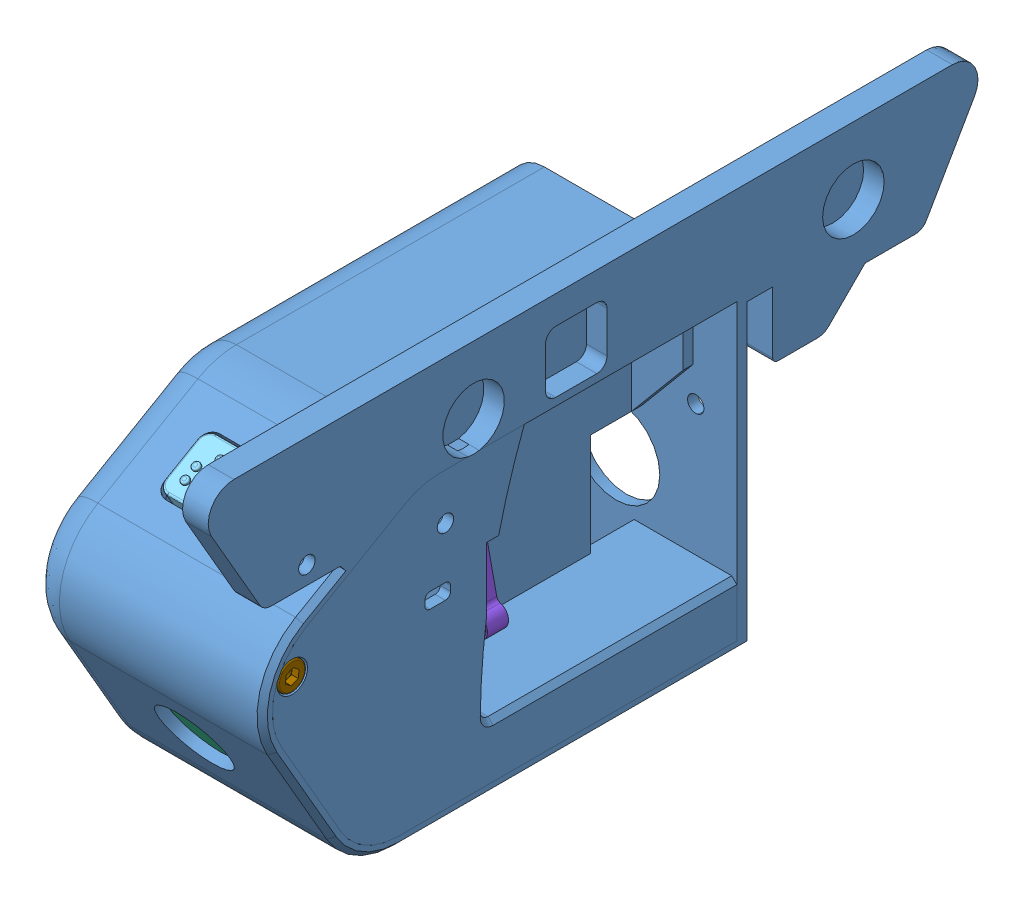
SolidWorks assembly Electronic box, configuration Default. Lengths in mm.
Overall size (46 78.25 150).
19 component instances, 9 part files, 31 mates.
Components (placement in the parent):
- Electronic box-1: Electronic box [Default] at (103.7468 101.0355 62.1495) size (46 78.25 150)
- Main PCB-1: Main PCB [Default] at (71.2468 84.0555 113.6495) x (0 0 -1) z (0 -1 0) size (59.38 19.5 46.8)
- Button PCB-1: Button PCB [Default] at (70.1673 63.8406 151.7276) x (1 0 0) z (0 0.866025 0.5) size (23 28.25 20.2)
  - Button PCB-1: Button PCB [Default] at (17.5795 4.2128 10.4054) size (22 28 18.6)
  - ButtonF-1: ButtonF [Default] at (24.8295 26.9628 23.0054) x (1 0 0) z (0 -1 0) size (8.5 5.6 11)
  - ButtonS-1: ButtonS [Default] at (10.3295 26.9628 23.0054) x (1 0 0) z (0 -1 0) size (8.5 5.6 11)
- Speaker-1: Speaker [Default] at (87.7468 61.2855 147.1199) x (0 0.866025 0.5) z (-1 0 0) size (19.8 4.4 19.8)
- Servo PCB-1: Servo PCB [Default] at (73.2468 46.7855 136.3495) size (25.5 14.5 62.2)
- Limit switch-1: Limit switch [Default] at (94.7468 80.2855 109.7827) x (0 -1 0) z (0 0 1) size (20.1 16 6.3)
- socket head cap screw_din-1: socket head cap screw_din [DIN 912 M3 x 6 --- 6N] at (74.2468 60.0355 72.1495) x (-1 0 0) z (0 0.924225 0.381849) size (9 5.5 5.5)
- socket head cap screw_din-5: socket head cap screw_din [DIN 912 M3 x 6 --- 6N] at (74.2468 92.5355 72.1495) x (-1 0 0) z (0 0.924225 0.381849) size (9 5.5 5.5)
- socket head cap screw_din-6: socket head cap screw_din [DIN 912 M3 x 6 --- 6N] at (74.2468 92.5355 95.1495) x (-1 0 0) z (0 0.924225 0.381849) size (9 5.5 5.5)
- socket head cap screw_din-7: socket head cap screw_din [DIN 912 M3 x 5 --- 5N] at (95.7468 51.3855 77.1495) x (0 -1 0) z (0 0 1) size (8 5.5 5.5)
- socket head cap screw_din-8: socket head cap screw_din [DIN 912 M3 x 5 --- 5N] at (76.2468 51.3855 77.1495) x (0 -1 0) z (0 0 1) size (8 5.5 5.5)
- socket head cap screw_din-9: socket head cap screw_din [DIN 912 M2 x 12 --- 12N] at (94.7468 70.7855 104.6327) x (0 0 1) z (-1 0 0) size (14 3.8 3.8)
- socket head cap screw_din-10: socket head cap screw_din [DIN 912 M2 x 12 --- 12N] at (94.7468 80.2855 104.6327) x (0 0 1) z (-1 0 0) size (14 3.8 3.8)
- socket head cap screw_din-11: socket head cap screw_din [DIN 912 M3 x 12 --- 12N] at (108.7468 82.0658 150.7791) x (-1 0 0) z (0 0.924225 0.381849) size (15 5.5 5.5)
- socket head cap screw_din-12: socket head cap screw_din [DIN 912 M3 x 8 --- 8N] at (103.4968 42.7855 107.1495) x (0 1 0) z (0 0 1) size (11 5.5 5.5)
- socket head cap screw_din-13: socket head cap screw_din [DIN 912 M3 x 8 --- 8N] at (103.4968 42.7855 74.1495) x (0 1 0) z (0 0 1) size (11 5.5 5.5)
Mates (geometry in assembly coordinates):
- Concentric2: concentric anti-aligned: cylinder of Electronic box-1 through (69.7468 60.0355 72.1495) axis (-1 0 0) radius 2.25; cylinder of Main PCB-1 through (69.7468 60.0355 72.1495) axis (1 0 0) radius 1.6
- Coincident2: coincident anti-aligned: plane of Electronic box-1 through (69.7468 60.0355 72.1495) normal (1 0 0); plane of Main PCB-1 through (69.7468 84.0555 113.6495) normal (-1 0 0)
- Concentric3: concentric aligned: cylinder of Main PCB-1 through (69.7468 60.0355 72.1495) axis (1 0 0) radius 1.6; cylinder of socket head cap screw_din-1 through (105.9968 60.0355 72.1495) axis (1 0 0) radius 2.75
- Coincident3: coincident anti-aligned: plane of Main PCB-1 through (71.2468 84.0555 113.6495) normal (1 0 0); plane of socket head cap screw_din-1 through (71.2468 58.9854 74.6912) normal (-1 0 0)
- Concentric6: concentric aligned: cylinder of Main PCB-1 through (69.7468 92.5355 72.1495) axis (1 0 0) radius 1.6; cylinder of socket head cap screw_din-5 through (105.9968 92.5355 72.1495) axis (1 0 0) radius 2.75
- Coincident6: coincident aligned: plane of Main PCB-1 through (71.2468 84.0555 113.6495) normal (-1 0 0); plane of socket head cap screw_din-5 through (71.2468 91.4854 74.6912) normal (-1 0 0)
- Concentric7: concentric aligned: cylinder of Main PCB-1 through (69.7468 92.5355 95.1495) axis (1 0 0) radius 1.6; cylinder of socket head cap screw_din-6 through (105.9968 92.5355 95.1495) axis (1 0 0) radius 2.75
- Coincident7: coincident aligned: plane of Main PCB-1 through (71.2468 84.0555 113.6495) normal (-1 0 0); plane of socket head cap screw_din-6 through (71.2468 91.4854 97.6912) normal (-1 0 0)
- Coincident9: coincident anti-aligned: plane of Electronic box-1 through (108.7468 51.2855 141.3464) normal (0 0.5 -0.866025); plane of Speaker-1 through (87.7468 61.2855 147.1199) normal (0 -0.5 0.866025)
- Concentric8: concentric anti-aligned: cylinder of Electronic box-1 through (87.7468 62.5355 144.9549) axis (0 -0.5 0.866025) radius 10.25; cylinder of Speaker-1 through (87.7468 63.4855 143.3094) axis (0 0.5 -0.866025) radius 9.9
- Width1: width anti-aligned: plane of Electronic box-1 through (91.7468 80.8656 146.3002) normal (0 -0.866025 -0.5); plane of Button PCB-1/Button PCB-1 through (62.7448 74.4062 154.1882) normal (0 0.866025 0.5); plane of Electronic box-1 through (87.7468 76.344 154.0819) normal (0 0.866025 0.5); plane of Button PCB-1/Button PCB-1 through (87.7468 74.9584 153.2819) normal (0 -0.866025 -0.5)
- Distance1: distance = 0.5 mm anti-aligned: plane of Electronic box-1 through (76.2468 77.7855 141.6351) normal (1 0 0); plane of Button PCB-1/Button PCB-1 through (76.7468 76.344 154.0819) normal (-1 0 0)
- Distance2: distance = 0.5 mm anti-aligned: plane of Button PCB-1/Button PCB-1 through (76.7468 76.344 154.0819) normal (0 -0.5 0.866025); plane of Electronic box-1 through (105.2033 74.6867 153.7024) normal (0 0.5 -0.866025)
- Concentric9: concentric aligned: cylinder of Electronic box-1 through (76.2468 46.7855 77.1495) axis (0 -1 0) radius 1.375; cylinder of Servo PCB-1 through (76.2468 48.3855 77.1495) axis (0 -1 0) radius 1.55
- Coincident10: coincident anti-aligned: plane of Electronic box-1 through (76.2468 46.7855 77.1495) normal (0 1 0); plane of Servo PCB-1 through (76.2468 46.7855 77.1495) normal (0 -1 0)
- Concentric10: concentric anti-aligned: cylinder of Servo PCB-1 through (95.7468 48.3855 77.1495) axis (0 -1 0) radius 1.55; cylinder of socket head cap screw_din-7 through (95.7468 83.1355 77.1495) axis (0 1 0) radius 2.75
- Coincident11: coincident anti-aligned: plane of Servo PCB-1 through (76.2468 48.3855 77.1495) normal (0 1 0); plane of socket head cap screw_din-7 through (98.4968 48.3855 77.1495) normal (0 -1 0)
- Concentric11: concentric anti-aligned: cylinder of Servo PCB-1 through (76.2468 48.3855 77.1495) axis (0 -1 0) radius 1.55; cylinder of socket head cap screw_din-8 through (76.2468 83.1355 77.1495) axis (0 1 0) radius 2.75
- Coincident12: coincident anti-aligned: plane of Servo PCB-1 through (76.2468 48.3855 77.1495) normal (0 1 0); plane of socket head cap screw_din-8 through (78.9968 48.3855 77.1495) normal (0 -1 0)
- Concentric24: concentric aligned: cylinder of Electronic box-1 through (94.7468 70.7855 167.1495) axis (0 0 -1) radius 1; cylinder of Limit switch-1 through (94.7468 70.7855 112.9327) axis (0 0 -1) radius 1.25
- Coincident23: coincident anti-aligned: plane of Electronic box-1 through (135.0512 85.7855 112.9327) normal (0 0 -1); plane of Limit switch-1 through (94.7468 80.2855 112.9327) normal (0 0 1)
- Concentric25: concentric aligned: cylinder of Limit switch-1 through (94.7468 70.7855 112.9327) axis (0 0 -1) radius 1.25; cylinder of socket head cap screw_din-9 through (94.7468 70.7855 72.8827) axis (0 0 -1) radius 1.9
- Coincident24: coincident anti-aligned: plane of Limit switch-1 through (94.7468 80.2855 106.6327) normal (0 0 -1); plane of socket head cap screw_din-9 through (94.7468 72.6855 106.6327) normal (0 0 1)
- Concentric26: concentric aligned: cylinder of Limit switch-1 through (94.7468 80.2855 112.9327) axis (0 0 -1) radius 1.25; cylinder of socket head cap screw_din-10 through (94.7468 80.2855 72.8827) axis (0 0 -1) radius 1.9
- Coincident25: coincident anti-aligned: plane of Limit switch-1 through (94.7468 80.2855 106.6327) normal (0 0 -1); plane of socket head cap screw_din-10 through (94.7468 82.1855 106.6327) normal (0 0 1)
- Concentric27: concentric aligned: cylinder of Electronic box-1 through (105.7468 82.0658 150.7791) axis (1 0 0) radius 3; cylinder of socket head cap screw_din-11 through (140.4968 82.0658 150.7791) axis (1 0 0) radius 2.75
- Coincident26: coincident anti-aligned: plane of Electronic box-1 through (105.7468 79.9256 146.2071) normal (1 0 0); plane of socket head cap screw_din-11 through (105.7468 81.0157 153.3207) normal (-1 0 0)
- Concentric28: concentric aligned: cylinder of Electronic box-1 through (103.4968 47.2855 107.1495) axis (0 -1 0) radius 1.6; cylinder of socket head cap screw_din-12 through (103.4968 11.0355 107.1495) axis (0 -1 0) radius 2.75
- Coincident27: coincident anti-aligned: plane of Electronic box-1 through (103.4968 45.7855 107.1495) normal (0 -1 0); plane of socket head cap screw_din-12 through (100.7468 45.7855 107.1495) normal (0 1 0)
- Concentric29: concentric aligned: cylinder of Electronic box-1 through (103.4968 47.2855 74.1495) axis (0 -1 0) radius 1.6; cylinder of socket head cap screw_din-13 through (103.4968 11.0355 74.1495) axis (0 -1 0) radius 2.75
- Coincident28: coincident anti-aligned: plane of Electronic box-1 through (103.4968 45.7855 74.1495) normal (0 -1 0); plane of socket head cap screw_din-13 through (100.7468 45.7855 74.1495) normal (0 1 0)
